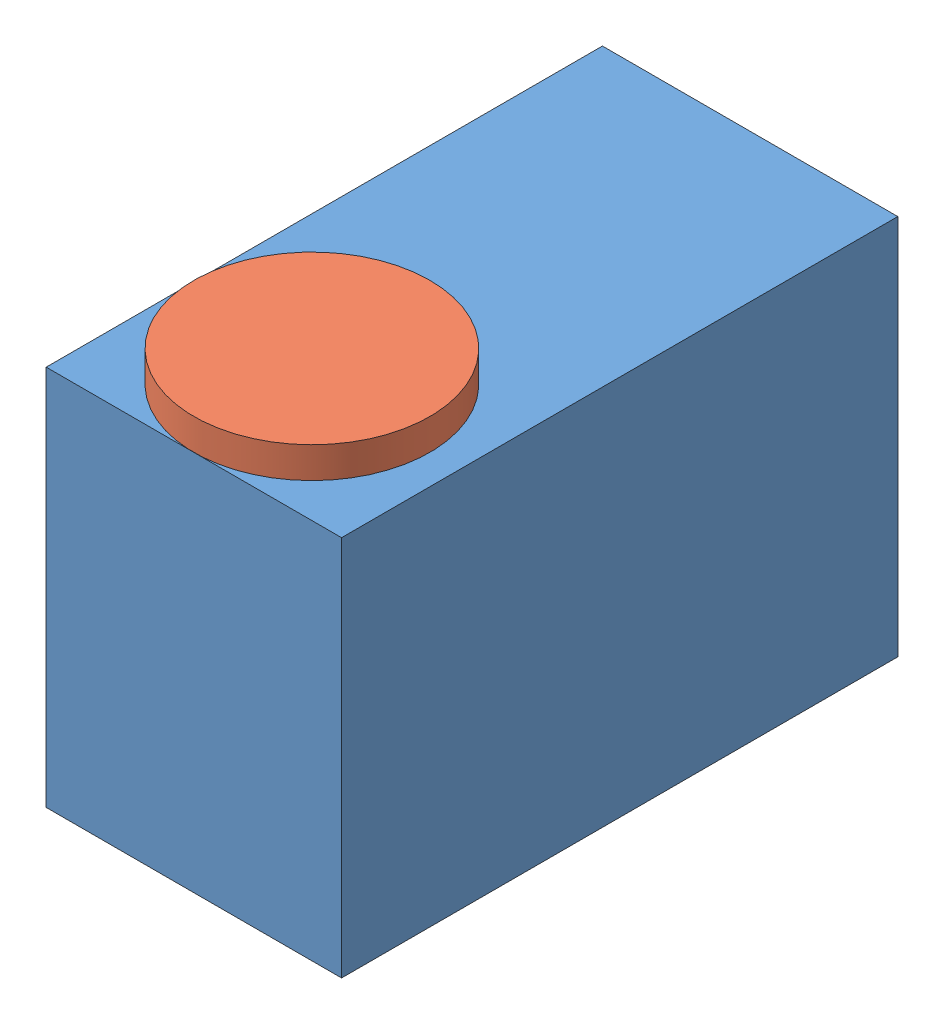
SolidWorks assembly motor1, configuration Default. Lengths in mm.
Overall size (25.89 33.2 48.22).
2 component instances, 2 part files, 3 mates.
Components (placement in the parent):
- body1-1: body1 [Default] at (-13.594 -17.6811 19.5512) size (23.78 30.7 44.78)
- horn1-1: horn1 [Default] at (-85.6017 36.16 60.249) x (-0.870676 0 0.491856) z (0 1 0) size (19 19 2.5)
Mates (geometry in assembly coordinates):
- Coincident1: coincident anti-aligned: plane of body1-1 through (-7.374 36.16 64.3312) normal (0 1 0); plane of horn1-1 through (4.516 36.16 54.8312) normal (0 -1 0)
- Tangent1: tangent aligned: plane of body1-1 through (-13.594 -17.6811 64.3312) normal (0 0 1); cylinder of horn1-1 through (4.516 38.66 54.8312) axis (0 -1 0) radius 9.5
- Perpendicular1: perpendicular: line of body1-1 through (16.406 36.16 64.3312) axis (0 0 -1); line of assembly
